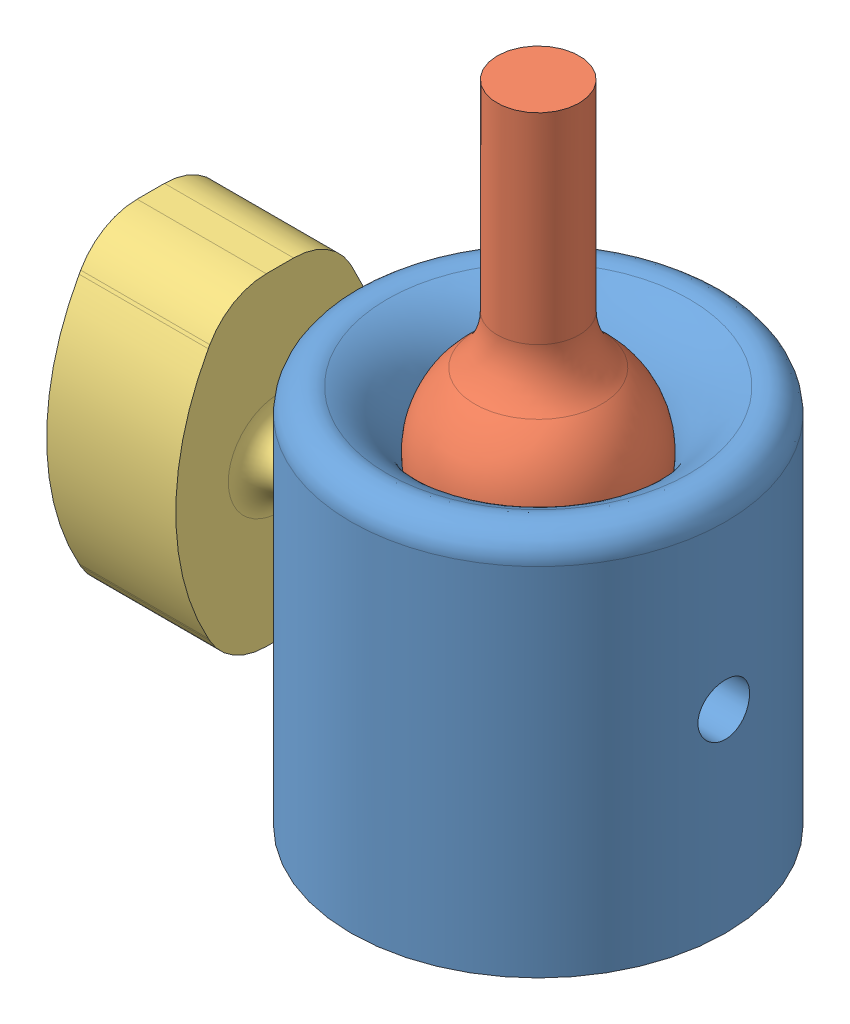
SolidWorks assembly BDT_S_A_21_v01, configuration Valor predeterminado. Lengths in mm.
Overall size (44.5 50 29).
3 component instances, 3 part files, 4 mates.
Components (placement in the parent):
- BDT_S_P_18_v01-1: BDT_S_P_18_v01 [Valor predeterminado] at origin size (29 29.58 29)
- BDT_S_P_19_v01-1: BDT_S_P_19_v01 [Valor predeterminado] at (0 25 0) x (0.004719 0 -0.999989) z (0.999989 0 0.004719) size (15 32.5 15)
- BDT_S_P_20_v01-1: BDT_S_P_20_v01 [Valor predeterminado] at (-20 15 0) x (0 0 1) z (-1 0 0) size (16.13 25 20.11)
Mates (geometry in assembly coordinates):
- Concêntrico1: concentric anti-aligned: cylinder of BDT_S_P_18_v01-1 through (0 13 0) axis (0 1 0) radius 7.5; circle of BDT_S_P_19_v01-1
- Distância2: distance = 50 mm anti-aligned: plane of BDT_S_P_19_v01-1 through (0 50 0) normal (0 1 0); plane of BDT_S_P_18_v01-1 through (0 0 0) normal (0 -1 0)
- Concêntrico3: concentric anti-aligned: cylinder of BDT_S_P_18_v01-1 through (-14.5 15 0) axis (1 0 0) radius 2; cylinder of BDT_S_P_20_v01-1 through (-10 15 0) axis (-1 0 0) radius 2
- Distância3: distance = 10 mm aligned: plane of assembly through (0 0 0) normal (1 0 0); plane of BDT_S_P_20_v01-1 through (-10 15 0) normal (1 0 0)
